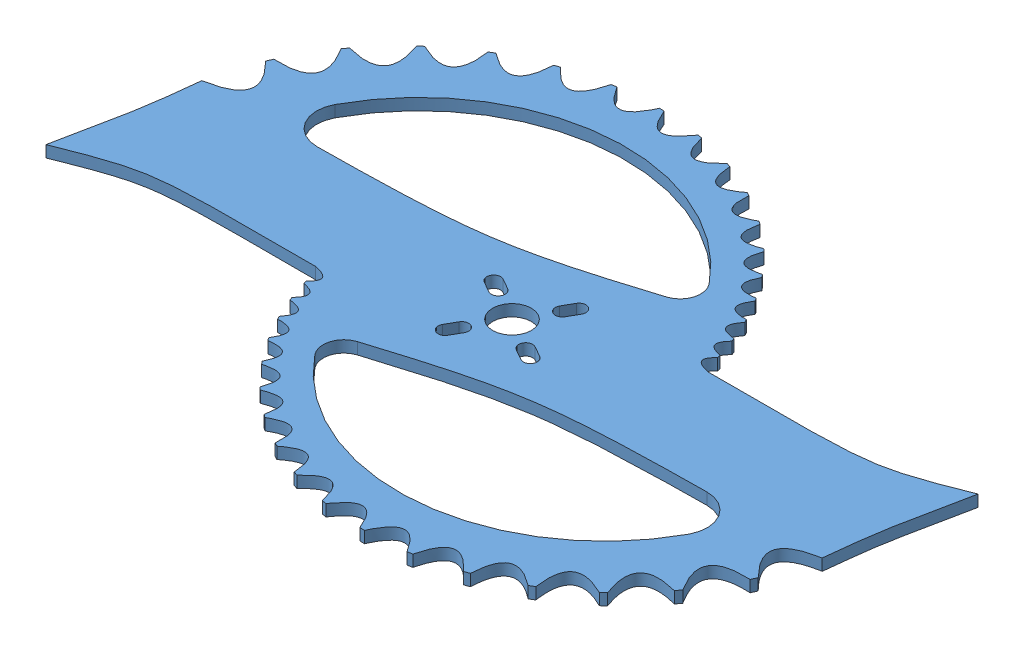
SolidWorks assembly ft-3mm-6in-bar, configuration Default. Lengths in mm.
Overall size (198.86 3.39 132.76).
3 component instances, 2 part files, 1 mates.
Components (placement in the parent):
- ft-3mm-6in-bar.IGS-1: ft-3mm-6in-bar.IGS [Default] at origin size (149.08 3.39 99.51) (hidden)
  - Component1.IGS-1: Component1.IGS [Default] at origin size (149.08 3.39 99.51)
- custom-8in^ft-3mm-6in-bar-1: custom-8in^ft-3mm-6in-bar [Default] at origin size (198.86 3.1 132.76) (virtual)
Mates (geometry in assembly coordinates):
- Coincident1: coordinate: point of custom^ft-3mm-6in-bar-1
